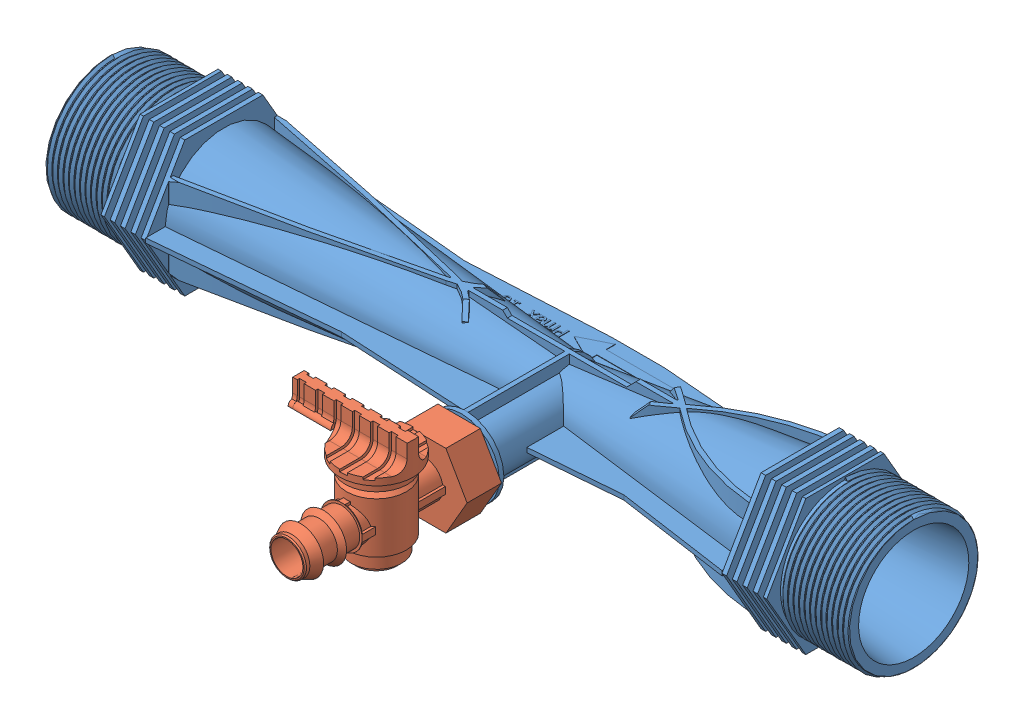
SolidWorks assembly VENTURI INJECTOR 2 INCH, configuration Default. Lengths in mm.
Overall size (351.09 63.22 157.01).
6 component instances, 5 part files, 0 mates.
Components (placement in the parent):
- VENTURI INJECTOR 2 INCH.stp-1: VENTURI INJECTOR 2 INCH.stp [Default] at origin size (351.09 63.22 157.01)
  - CORPS.stp-1: CORPS.stp [Default] at (-171.8938 -7.8737 -13) size (351.09 60.66 94.65)
  - VANETTE.stp-1: VANETTE.stp [Default] at (28.1062 -7.8737 35) x (0 0 -1) z (1 0 0) size (75.79 51 52.48)
  - RESSORT.stp-1: RESSORT.stp [Default] at (28.1062 -7.8737 39) x (0 -1 0) z (1 0 0) size (16.68 35.12 16.68)
  - JOINT.stp-1: JOINT.stp [Default] at (28.1062 -7.8737 39) x (-1 0 0) z (0 0 -1) size (17 17 12)
  - JOINT PLASTIQUE.stp-1: JOINT PLASTIQUE.stp [Default] at (28.1062 -7.8737 45) size (23 23 2)
